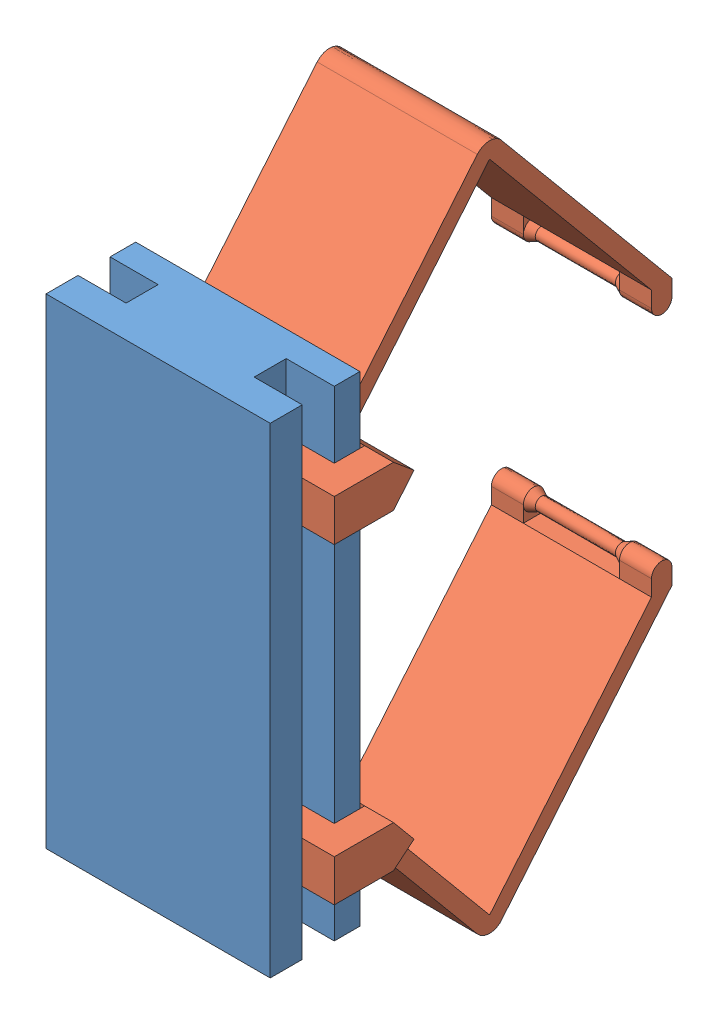
SolidWorks assembly 抓手test_1_0, configuration 默认. Lengths in mm.
Overall size (90 214.4 146.29).
3 component instances, 2 part files, 4 mates.
Components (placement in the parent):
- 柔性导轨-1: 柔性导轨 [默认] at (-43.9468 -65.7615 164) size (70 150 28)
- 抓手右-1: 抓手右 [默认] at (16.0532 -32.9799 85.5) x (0 -1 0) z (0 0 -1) size (73.86 90 146.29)
- 抓手右-2: 抓手右 [默认] at (-33.9468 51.423 85.5) x (0 1 0) z (0 0 -1) size (73.86 90 146.29)
Mates (geometry in assembly coordinates):
- 重合1: coincident anti-aligned: plane of 柔性导轨-1 through (-28.9468 84.2385 144) normal (-1 0 0); plane of 抓手右-1 through (-28.9468 -32.9799 85.5) normal (1 0 0)
- 重合2: coincident anti-aligned: plane of 柔性导轨-1 through (-28.9468 84.2385 154) normal (0 0 -1); plane of 抓手右-1 through (16.0532 -32.9799 154) normal (0 0 1)
- 重合5: coincident anti-aligned: plane of 柔性导轨-1 through (11.0532 84.2385 154) normal (1 0 0); plane of 抓手右-2 through (11.0532 51.423 85.5) normal (-1 0 0)
- 重合7: coincident anti-aligned: plane of 柔性导轨-1 through (26.0532 84.2385 154) normal (0 0 -1); plane of 抓手右-2 through (-33.9468 51.423 154) normal (0 0 1)
